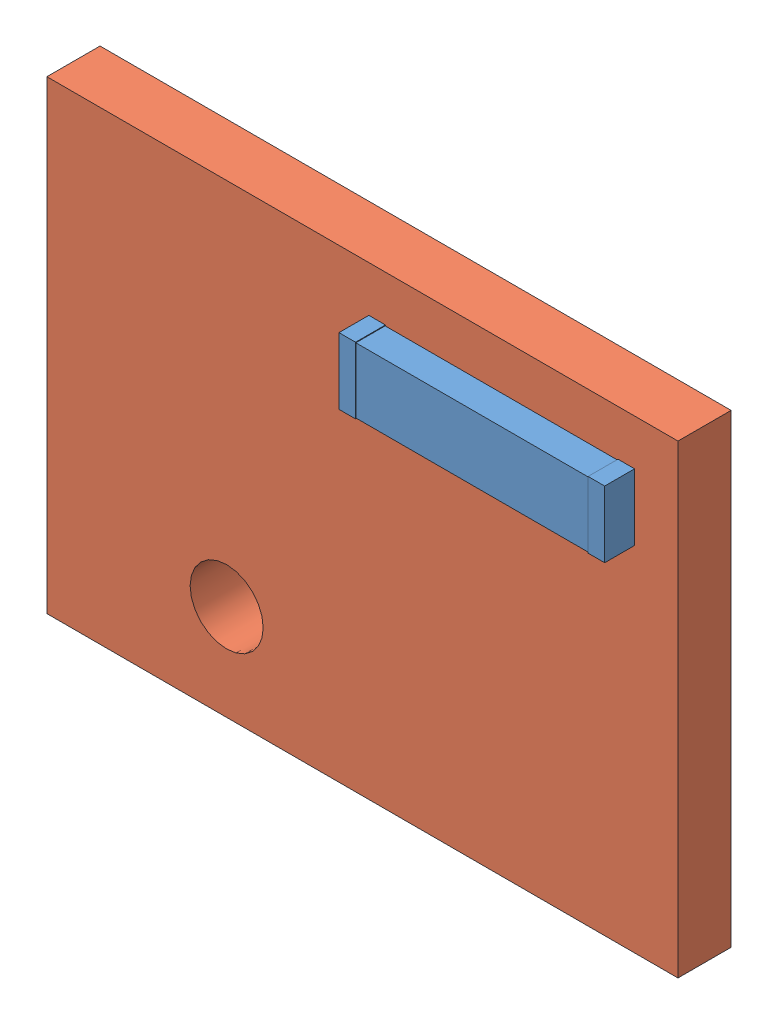
SolidWorks assembly Antena, configuration Default. Lengths in mm.
Overall size (19 14 2.55).
3 component instances, 2 part files, 0 mates.
Components (placement in the parent):
- 0915AT43A0026E-1: 0915AT43A0026E [Default] at (2.7432 4.6736 1.65) size (8 2 0.9)
  - COMPOUND-1: COMPOUND [Default] at origin size (8 2 0.9)
- COMPOUND_2-1: COMPOUND_2 [Default] at origin size (19 14 1.6)
